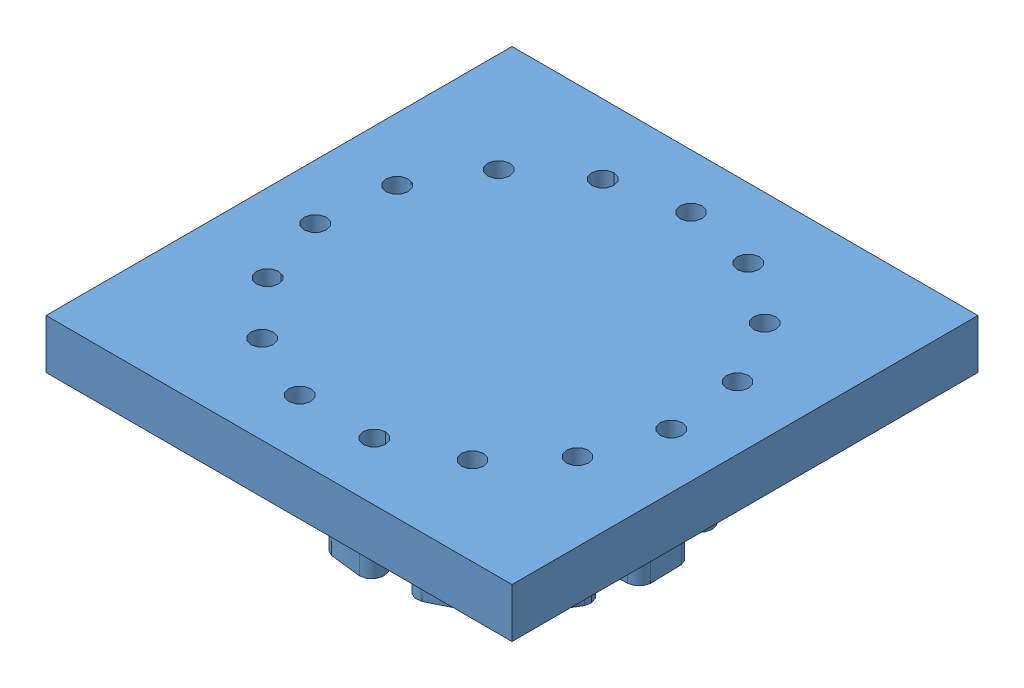
SolidWorks assembly Moldy2v2, configuration Default. Lengths in mm.
Overall size (42 13.6 42).
2 component instances, 2 part files, 3 mates.
Components (placement in the parent):
- COmpression Wheel v5-1: COmpression Wheel v5 [Default] at origin size (32.5 10 32.5) (hidden)
- Cavity No Cavityv2-1: Cavity No Cavityv2 [Default] at (0 9.65 0) x (1 0 0) z (0 0 -1) size (42 13.6 42)
Mates (geometry in assembly coordinates):
- Coincident4: coincident aligned: plane of Cavity No Cavityv2-1 through (0 3.15 0) normal (0 -1 0); circle of COmpression Wheel v5-1
- Coincident2: coincident aligned: plane of COmpression Wheel v5-1 through (0 0 0) normal (1 0 0); plane of Cavity No Cavityv2-1 through (0 9.65 0) normal (1 0 0)
- Coincident3: coincident anti-aligned: plane of COmpression Wheel v5-1 through (0 0 0) normal (0 0 1); plane of Cavity No Cavityv2-1 through (0 9.65 0) normal (0 0 -1)
